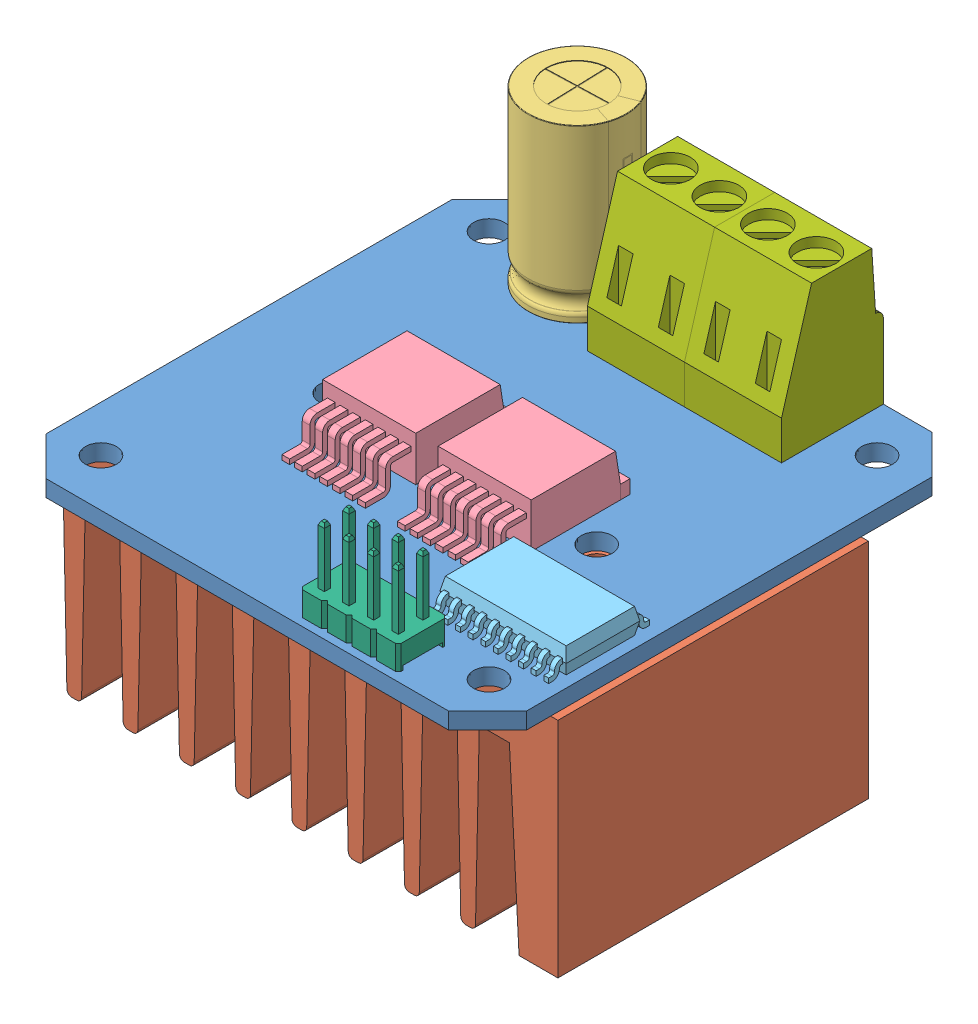
SolidWorks assembly BTS7960 43A HIGH POWER H BRIDGE MODULE, configuration Default. Lengths in mm.
Overall size (51 42.4 49.96).
9 component instances, 7 part files, 22 mates.
Components (placement in the parent):
- PCB, BTS7960 43A HIGH POWER H BRIDGE MODULE-1: PCB, BTS7960 43A HIGH POWER H BRIDGE MODULE [Default] at origin size (49.5 1.7 49.8)
- HEATSINK, BTS7960 43A HIGH POWER H BRIDGE MODULE-1: HEATSINK, BTS7960 43A HIGH POWER H BRIDGE MODULE [Default] at (0 0 2.4) size (51 23 32.02)
- ALUMINUM ELECTROLYTIC CAPACITOR, 330 uF, BTS7960 43A HIGH POWER H BRIDGE MODULE-1: ALUMINUM ELECTROLYTIC CAPACITOR, 330 uF, BTS7960 43A HIGH POWER H BRIDGE MODULE [Default] at (-10.75 1.8 -19.85) x (0.999469 0 -0.032584) z (0.032584 0 0.999469) size (10.1 18.7 10.1)
- BTN7960 IC, BTS7960 43A HIGH POWER H BRIDGE MODULE-1: BTN7960 IC, BTS7960 43A HIGH POWER H BRIDGE MODULE [Default] at (5.95 1.7 1.8) x (-1 0 0) z (0 0 -1) size (9.6 4.6 14.9)
- NXP 74HC244D, BUFFER AND LINE DRIVER, BTS7960 43A HIGH POWER H BRIDGE MODULE-1: NXP 74HC244D, BUFFER AND LINE DRIVER, BTS7960 43A HIGH POWER H BRIDGE MODULE [Default] at (17.35 3 12.1) size (13 2.6 10.4)
- 8 PIN HEADER, IC, BTS7960 43A HIGH POWER H BRIDGE MODULE-1: 8 PIN HEADER, IC, BTS7960 43A HIGH POWER H BRIDGE MODULE [Default] at (-34.78 4.2 20.29) x (0 0 -1) z (-1 0 0) size (5.08 11.6 10.16)
- EUROSTYLE TERMINAL BLOCK 2 POS 5.0 MM RA PLUG, BTS7960 43A HIGH POWER H BRIDGE MODULE-1: EUROSTYLE TERMINAL BLOCK 2 POS 5.0 MM RA PLUG, BTS7960 43A HIGH POWER H BRIDGE MODULE [Default] at (0.75 4.2 -6.5) size (10 14.5 10.5)
- EUROSTYLE TERMINAL BLOCK 2 POS 5.0 MM RA PLUG, BTS7960 43A HIGH POWER H BRIDGE MODULE-2: EUROSTYLE TERMINAL BLOCK 2 POS 5.0 MM RA PLUG, BTS7960 43A HIGH POWER H BRIDGE MODULE [Default] at (10.75 4.2 -6.5) size (10 14.5 10.5)
- BTN7960 IC, BTS7960 43A HIGH POWER H BRIDGE MODULE-2: BTN7960 IC, BTS7960 43A HIGH POWER H BRIDGE MODULE [Default] at (-5.95 1.7 1.8) x (-1 0 0) z (0 0 -1) size (9.6 4.6 14.9)
Mates (geometry in assembly coordinates):
- Coincident1: coordinate: point of PCB, BTS7960 43A HIGH POWER H BRIDGE MODULE-1
- Coincident2: coincident anti-aligned: plane of PCB, BTS7960 43A HIGH POWER H BRIDGE MODULE-1 through (0 0 0) normal (0 -1 0); plane of HEATSINK, BTS7960 43A HIGH POWER H BRIDGE MODULE-1 through (0 0 2.4) normal (0 1 0)
- Distance1: distance = 6.5 mm aligned: plane of HEATSINK, BTS7960 43A HIGH POWER H BRIDGE MODULE-1 through (-25.5 -4.5 18.4) normal (0 0 1); plane of PCB, BTS7960 43A HIGH POWER H BRIDGE MODULE-1 through (-24.75 1.7 24.9) normal (0 0 1)
- Coincident4: coincident anti-aligned: plane of PCB, BTS7960 43A HIGH POWER H BRIDGE MODULE-1 through (0 1.7 0) normal (0 1 0); plane of ALUMINUM ELECTROLYTIC CAPACITOR, 330 uF, BTS7960 43A HIGH POWER H BRIDGE MODULE-1 through (-10.75 1.7 -19.85) normal (0 -1 0)
- Distance2: distance = 14 mm: line of ALUMINUM ELECTROLYTIC CAPACITOR, 330 uF, BTS7960 43A HIGH POWER H BRIDGE MODULE-1 through (-10.75 4.6983 -19.85) axis (0 1 0); plane of PCB, BTS7960 43A HIGH POWER H BRIDGE MODULE-1 through (-24.75 1.7 -24.9) normal (-1 0 0)
- Tangent1: tangent aligned: cylinder of ALUMINUM ELECTROLYTIC CAPACITOR, 330 uF, BTS7960 43A HIGH POWER H BRIDGE MODULE-1 through (-10.75 4.7 -19.85) axis (0 1 0) radius 5.05; plane of PCB, BTS7960 43A HIGH POWER H BRIDGE MODULE-1 through (-24.75 1.7 -24.9) normal (0 0 -1)
- Coincident5: coincident anti-aligned: plane of PCB, BTS7960 43A HIGH POWER H BRIDGE MODULE-1 through (0 1.7 0) normal (0 1 0); plane of BTN7960 IC, BTS7960 43A HIGH POWER H BRIDGE MODULE-1 through (1.15 1.7 -2.8) normal (0 -1 0)
- Coincident6: coincident aligned: plane of HEATSINK, BTS7960 43A HIGH POWER H BRIDGE MODULE-1 through (0 0 2.4) normal (1 0 0)
- Distance4: distance = 14 mm aligned: plane of BTN7960 IC, BTS7960 43A HIGH POWER H BRIDGE MODULE-1 through (10.75 1.7 1.8) normal (1 0 0); plane of PCB, BTS7960 43A HIGH POWER H BRIDGE MODULE-1 through (24.75 1.7 -24.9) normal (1 0 0)
- Coincident7: coincident anti-aligned: plane of PCB, BTS7960 43A HIGH POWER H BRIDGE MODULE-1 through (0 1.7 0) normal (0 1 0); plane of NXP 74HC244D, BUFFER AND LINE DRIVER, BTS7960 43A HIGH POWER H BRIDGE MODULE-1 through (17.35 1.7 12.1) normal (0 -1 0)
- Distance5: distance = 0.9 mm: plane of PCB, BTS7960 43A HIGH POWER H BRIDGE MODULE-1 through (24.75 1.7 -24.9) normal (1 0 0); line of NXP 74HC244D, BUFFER AND LINE DRIVER, BTS7960 43A HIGH POWER H BRIDGE MODULE-1 through (23.85 3 15.9) axis (0 0 -1)
- Distance6: distance = 9 mm: plane of PCB, BTS7960 43A HIGH POWER H BRIDGE MODULE-1 through (-24.75 1.7 24.9) normal (0 0 1); line of NXP 74HC244D, BUFFER AND LINE DRIVER, BTS7960 43A HIGH POWER H BRIDGE MODULE-1 through (10.85 3 15.9) axis (1 0 0)
- Coincident8: coincident anti-aligned: plane of PCB, BTS7960 43A HIGH POWER H BRIDGE MODULE-1 through (0 1.7 0) normal (0 1 0); plane of 8 PIN HEADER, IC, BTS7960 43A HIGH POWER H BRIDGE MODULE-1 through (-34.78 1.7 22.53) normal (0 -1 0)
- Distance7: distance = 0.8 mm aligned: plane of 8 PIN HEADER, IC, BTS7960 43A HIGH POWER H BRIDGE MODULE-1 through (12.51 1.7 24.1) normal (0 0 1); plane of PCB, BTS7960 43A HIGH POWER H BRIDGE MODULE-1 through (-24.75 1.7 24.9) normal (0 0 1)
- Distance8: distance = 10 mm aligned: plane of 8 PIN HEADER, IC, BTS7960 43A HIGH POWER H BRIDGE MODULE-1 through (14.75 1.7 23.8) normal (1 0 0); plane of PCB, BTS7960 43A HIGH POWER H BRIDGE MODULE-1 through (24.75 1.7 -24.9) normal (1 0 0)
- Distance9: distance = 18.5 mm aligned: plane of BTN7960 IC, BTS7960 43A HIGH POWER H BRIDGE MODULE-2 through (-10.75 1.7 6.4) normal (0 0 1); plane of PCB, BTS7960 43A HIGH POWER H BRIDGE MODULE-1 through (-24.75 1.7 24.9) normal (0 0 1)
- Coincident9: coincident anti-aligned: plane of EUROSTYLE TERMINAL BLOCK 2 POS 5.0 MM RA PLUG, BTS7960 43A HIGH POWER H BRIDGE MODULE-1 through (5.75 4.2 -6.5) normal (1 0 0); plane of EUROSTYLE TERMINAL BLOCK 2 POS 5.0 MM RA PLUG, BTS7960 43A HIGH POWER H BRIDGE MODULE-2 through (5.75 4.2 -6.5) normal (-1 0 0)
- Coincident10: coincident aligned: plane of EUROSTYLE TERMINAL BLOCK 2 POS 5.0 MM RA PLUG, BTS7960 43A HIGH POWER H BRIDGE MODULE-1 through (-4.25 16.2 -24.3) normal (0 1 0); plane of EUROSTYLE TERMINAL BLOCK 2 POS 5.0 MM RA PLUG, BTS7960 43A HIGH POWER H BRIDGE MODULE-2 through (5.75 16.2 -24.3) normal (0 1 0)
- Coincident11: coincident aligned: plane of EUROSTYLE TERMINAL BLOCK 2 POS 5.0 MM RA PLUG, BTS7960 43A HIGH POWER H BRIDGE MODULE-1 through (20.7146 5.7 -14.4) normal (0 0 1); plane of EUROSTYLE TERMINAL BLOCK 2 POS 5.0 MM RA PLUG, BTS7960 43A HIGH POWER H BRIDGE MODULE-2 through (30.7146 5.7 -14.4) normal (0 0 1)
- Coincident12: coincident anti-aligned: plane of PCB, BTS7960 43A HIGH POWER H BRIDGE MODULE-1 through (0 1.7 0) normal (0 1 0); plane of EUROSTYLE TERMINAL BLOCK 2 POS 5.0 MM RA PLUG, BTS7960 43A HIGH POWER H BRIDGE MODULE-2 through (10.75 1.7 -6.5) normal (0 -1 0)
- Coincident13: coincident aligned: plane of PCB, BTS7960 43A HIGH POWER H BRIDGE MODULE-1 through (-24.75 1.7 -24.9) normal (0 0 -1); plane of EUROSTYLE TERMINAL BLOCK 2 POS 5.0 MM RA PLUG, BTS7960 43A HIGH POWER H BRIDGE MODULE-2 through (5.75 0.7 -24.9) normal (0 0 -1)
- Distance10: distance = 9 mm aligned: plane of EUROSTYLE TERMINAL BLOCK 2 POS 5.0 MM RA PLUG, BTS7960 43A HIGH POWER H BRIDGE MODULE-2 through (15.75 4.2 -6.5) normal (1 0 0); plane of PCB, BTS7960 43A HIGH POWER H BRIDGE MODULE-1 through (24.75 1.7 -24.9) normal (1 0 0)
